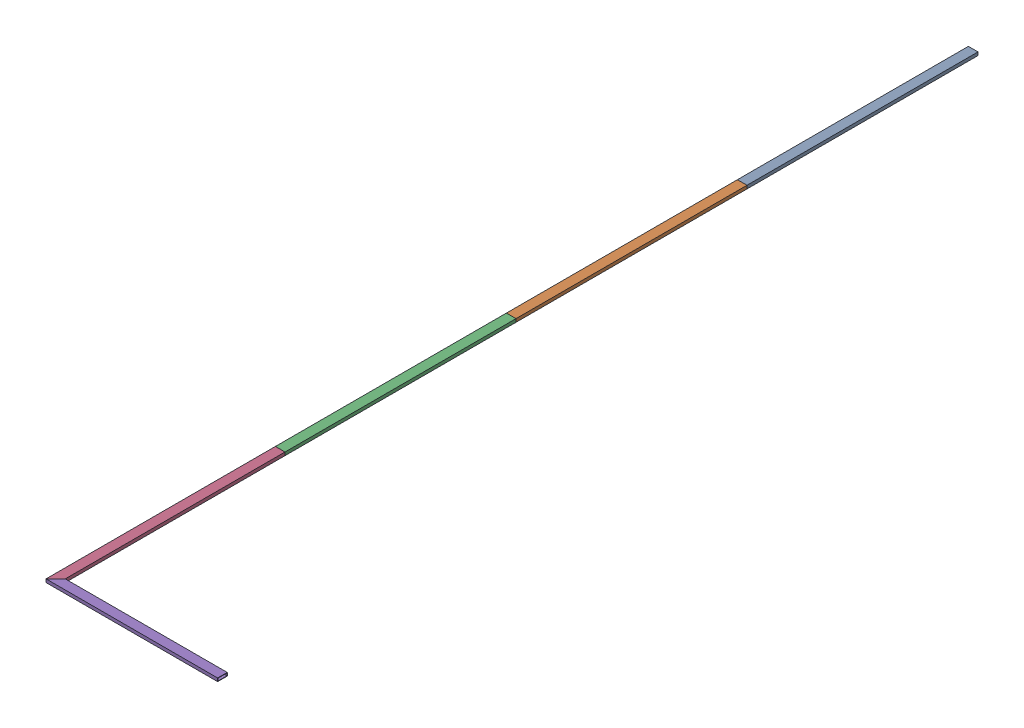
SolidWorks assembly GE-16085_ASM, configuration Default. Lengths in mm.
Overall size (1358.9 25.4 7302.5).
5 component instances, 3 part files, 0 mates.
Components (placement in the parent):
- GE-16086-1: GE-16086 [Default] at origin size (76.2 25.4 1828.8)
- GE-16086-2: GE-16086 [Default] at (0 0 1828.8) size (76.2 25.4 1828.8)
- GE-16086-3: GE-16086 [Default] at (0 0 3657.6) size (76.2 25.4 1828.8)
- GE-16087-1: GE-16087 [Default] at (0 0 5480.05) size (76.2 25.4 1816.1)
- GE-16088-1: GE-16088 [Default] at (641.35 0 6350) x (0 0 -1) z (-1 0 0) size (76.2 25.4 1358.9)
